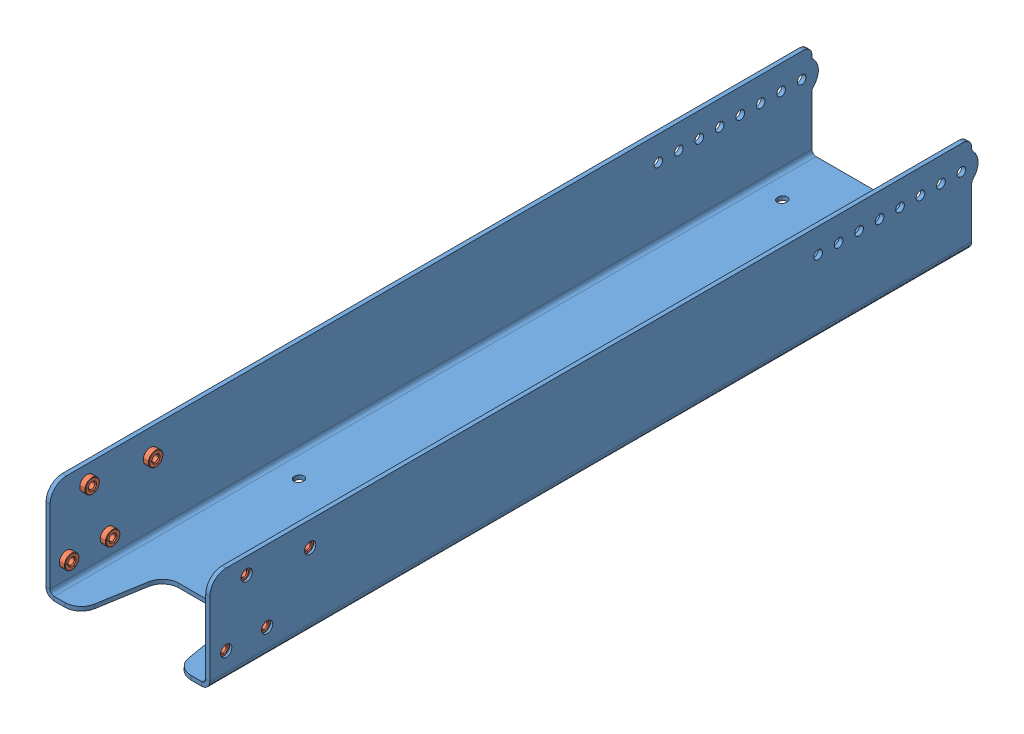
SolidWorks assembly GE-22379, configuration Default. Lengths in mm.
Overall size (127 76.2 595.52).
9 component instances, 2 part files, 11 mates.
Components (placement in the parent):
- GE-22379-01-1: GE-22379-01 [Default] at (0 3.175 -301.625) x (0 0 -1) z (1 0 0) size (595.52 76.2 127)
- pem_clinchnut_.25_20_.054-2: pem_clinchnut_.25_20_.054 [Default] at (-61.6966 63.5 -28.575) x (1 0 0) z (0 0.139507 0.990221) size (5.69 11.18 11.18)
- pem_clinchnut_.25_20_.054-3: pem_clinchnut_.25_20_.054 [Default] at (-61.6966 57.15 -77.7875) x (1 0 0) z (0 0.139507 0.990221) size (5.69 11.18 11.18)
- pem_clinchnut_.25_20_.054-4: pem_clinchnut_.25_20_.054 [Default] at (61.6966 57.15 -77.7875) x (-1 0 0) z (0 -0.990081 0.140498) size (5.69 11.18 11.18)
- pem_clinchnut_.25_20_.054-5: pem_clinchnut_.25_20_.054 [Default] at (61.6966 63.5 -28.575) x (-1 0 0) z (0 -0.990081 0.140498) size (5.69 11.18 11.18)
- pem_clinchnut_.25_20_.054-6: pem_clinchnut_.25_20_.054 [Default] at (61.6966 20.6375 -12.7) x (-1 0 0) z (0 -0.990081 0.140498) size (5.69 11.18 11.18)
- pem_clinchnut_.25_20_.054-7: pem_clinchnut_.25_20_.054 [Default] at (61.6966 20.6375 -44.45) x (-1 0 0) z (0 -0.990081 0.140498) size (5.69 11.18 11.18)
- pem_clinchnut_.25_20_.054-8: pem_clinchnut_.25_20_.054 [Default] at (-61.6966 20.6375 -12.7) x (1 0 0) z (0 0.139507 0.990221) size (5.69 11.18 11.18)
- pem_clinchnut_.25_20_.054-9: pem_clinchnut_.25_20_.054 [Default] at (-61.6966 20.6375 -44.45) x (1 0 0) z (0 0.139507 0.990221) size (5.69 11.18 11.18)
Mates (geometry in assembly coordinates):
- Coincident1: coincident anti-aligned: plane of GE-22379-01-1 through (0 0 -301.625) normal (0 -1 0)
- Coincident2: coincident aligned: plane of GE-22379-01-1 through (0 3.175 -301.625) normal (1 0 0)
- Coincident3: coincident aligned: plane of GE-22379-01-1 through (-63.5 76.2 0) normal (0 0 1)
- Concentric11: concentric aligned: cylinder of GE-22379-01-1 through (63.5 63.5 -28.575) axis (1 0 0) radius 4.3688; cylinder of pem_clinchnut_.25_20_.054-2 through (-58.3336 63.5 -28.575) axis (1 0 0) radius 5.588
- Coincident41: coincident anti-aligned: plane of GE-22379-01-1 through (-60.325 3.175 -301.625) normal (1 0 0); plane of pem_clinchnut_.25_20_.054-2 through (-60.325 63.8898 -25.8083) normal (-1 0 0)
- Concentric21: concentric aligned: cylinder of GE-22379-01-1 through (63.5 57.15 -77.7875) axis (1 0 0) radius 4.3688; cylinder of pem_clinchnut_.25_20_.054-3 through (-58.3336 57.15 -77.7875) axis (1 0 0) radius 5.588
- Coincident51: coincident anti-aligned: plane of GE-22379-01-1 through (-60.325 3.175 -301.625) normal (1 0 0); plane of pem_clinchnut_.25_20_.054-3 through (-60.325 57.5398 -75.0208) normal (-1 0 0)
- Concentric31: concentric anti-aligned: cylinder of GE-22379-01-1 through (63.5 57.15 -77.7875) axis (1 0 0) radius 4.3688; cylinder of pem_clinchnut_.25_20_.054-4 through (58.3336 57.15 -77.7875) axis (-1 0 0) radius 5.588
- Coincident61: coincident anti-aligned: plane of GE-22379-01-1 through (60.325 3.175 -301.625) normal (-1 0 0); plane of pem_clinchnut_.25_20_.054-4 through (60.325 54.3837 -77.3949) normal (1 0 0)
- Concentric41: concentric anti-aligned: cylinder of GE-22379-01-1 through (63.5 63.5 -28.575) axis (1 0 0) radius 4.3688; cylinder of pem_clinchnut_.25_20_.054-5 through (58.3336 63.5 -28.575) axis (-1 0 0) radius 5.588
- Coincident71: coincident anti-aligned: plane of GE-22379-01-1 through (60.325 3.175 -301.625) normal (-1 0 0); plane of pem_clinchnut_.25_20_.054-5 through (60.325 60.7337 -28.1824) normal (1 0 0)
